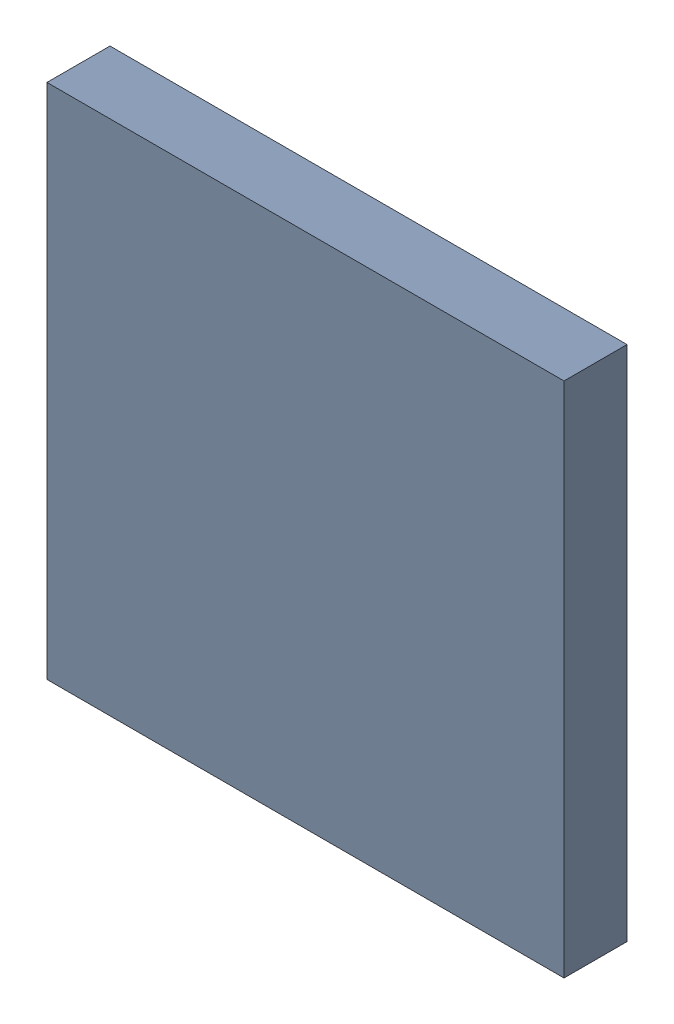
SolidWorks assembly U1, configuration Default. Lengths in mm.
Overall size (4.1 4.1 0.5).
2 component instances, 1 part files, 0 mates.
Components (placement in the parent):
- 870941920-1: 870941920 [Default] at (55.7522 32.8146 0) size (4.1 4.1 0.5)
  - Extruded_20-1: Extruded_20 [Default] at origin size (4.1 4.1 0.5)
